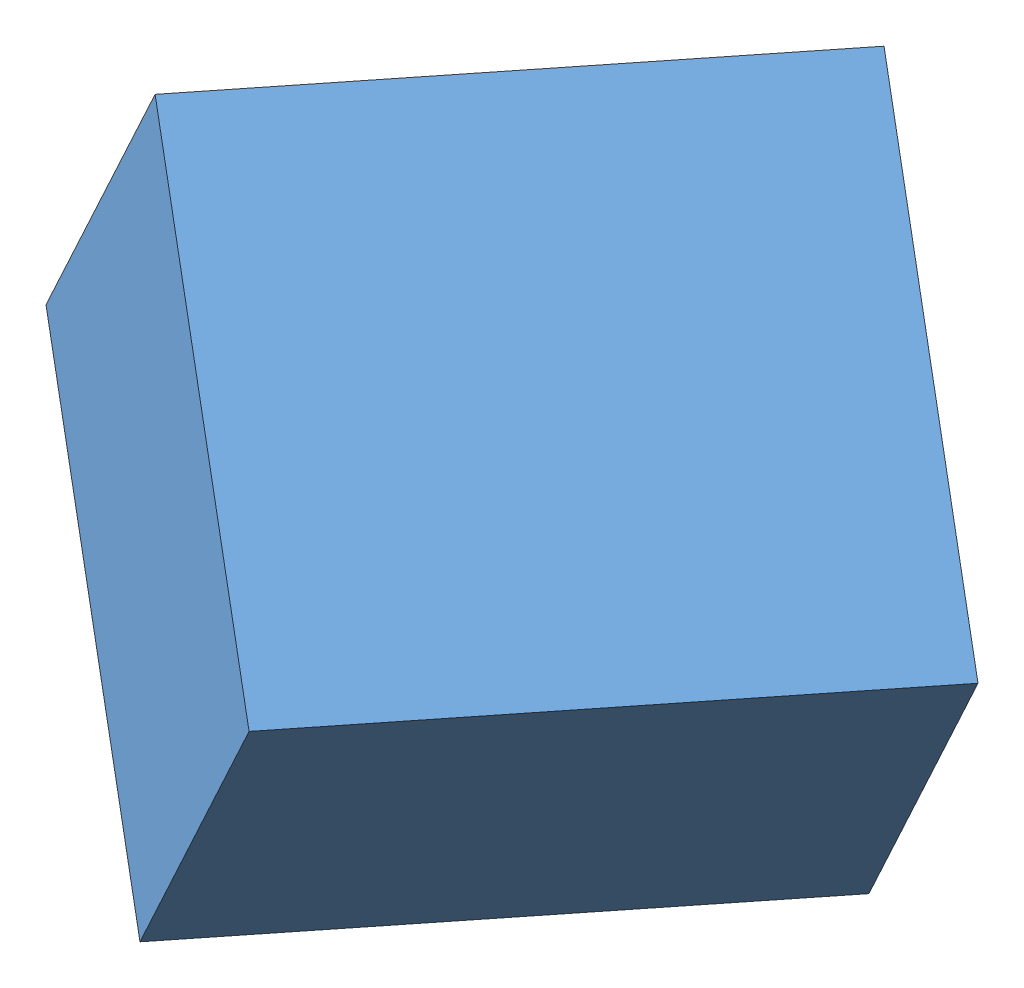
SolidWorks assembly outer box assm, configuration Default. Lengths in mm.
Overall size (884.81 707 841.62).
7 component instances, 4 part files, 4 mates.
Components (placement in the parent):
- outer box-1: outer box [Default] at (149.9225 60.4117 864.6868) x (0.670941 -0.568186 0.476448) z (-0.534317 0.075059 0.841945) size (520 450 570)
- door-2: door [Default] at (300.177 282.152 368.6335) x (0.673269 -0.564459 0.477593) z (-0.511092 -0.822041 -0.251065) size (45.2 454 14.29) (flexible)
  - glass-1: glass [Default] at (265.3341 251.2895 348.813) size (320 460 20)
  - hinge1-1: hinge1 [Default] at (90.3342 458.2895 360.7596) x (0 1 0) z (-0.004541 0 0.99999) size (40 25.5 6)
  - hinge2-1: hinge2 [Default] at (115.3341 458.2895 360.813) x (0 1 0) z (0 0 -1) size (40 25 5)
  - hinge2-2: hinge2 [Default] at (115.3341 44.2895 360.813) x (0 1 0) z (0 0 -1) size (40 25 5)
  - hinge1-2: hinge1 [Default] at (90.3342 44.2895 360.7596) x (0 1 0) z (-0.004541 0 0.99999) size (40 25.5 6)
Mates (geometry in assembly coordinates):
- Coincident10: coincident: plane of outer box-1 through (-142.876 24.1347 688.0431) normal (-0.514143 -0.81947 -0.253231); plane of door-2/hinge1-1 through (-67.2285 -29.3594 707.5633) normal (0.514143 0.81947 0.253231)
- Coincident11: coincident: circle of outer box-1; circle of door-2/hinge1-2
- Coincident12: coincident: circle of outer box-1; circle of door-2/hinge1-2
- Concentric1: concentric: cylinder of outer box-1 through (-55.1409 -22.1405 699.1504) axis (-0.514143 -0.81947 -0.253231) radius 2.5; cylinder of door-2/hinge1-1 through (-62.3389 -33.613 695.6051) axis (0.514143 0.81947 0.253231) radius 2.5
